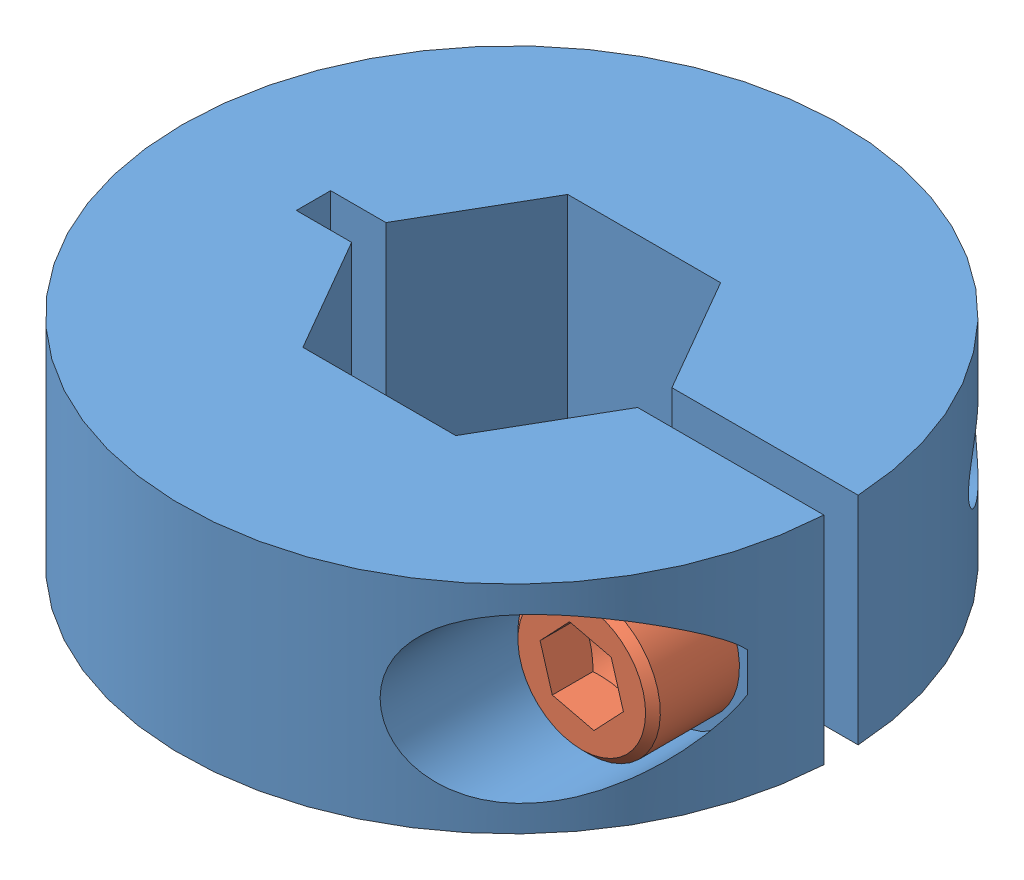
SolidWorks assembly 500 Hex Collar Clamp, configuration Default. Lengths in mm.
Overall size (32.26 10.41 31.75).
2 component instances, 2 part files, 0 mates.
Components (placement in the parent):
- Hex Collar 500-1: Hex Collar 500 [Default] at (-65.2624 31.6086 9.4318) size (31.73 10.41 31.75)
- 8-32 x 0375 SHCS-1: 8-32 x 0375 SHCS [Default] at (-53.7269 36.8156 13.4323) x (0 0 -1) z (0.687397 0.726282 0) size (13.71 6.86 6.86)
